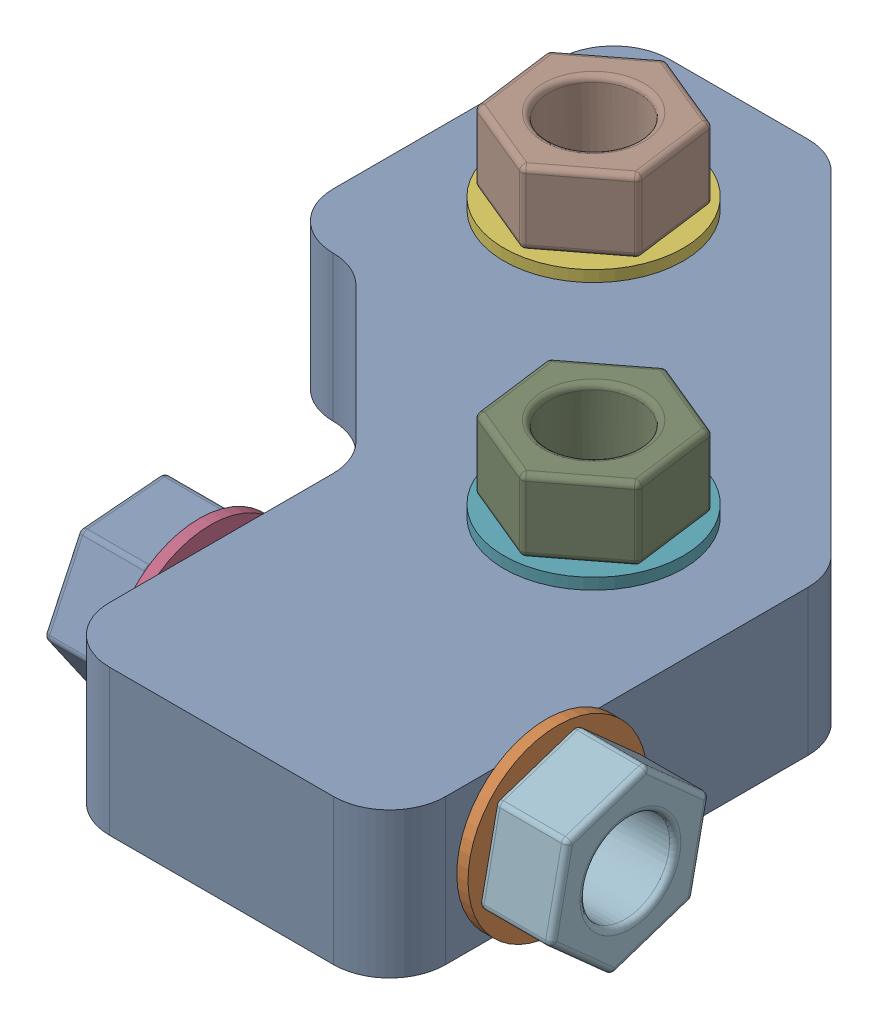
SolidWorks assembly Middle Corner with Washers and Nuts, configuration Default. Lengths in mm.
Overall size (59.5 28 72).
13 component instances, 3 part files, 12 mates.
Components (placement in the parent):
- Corner (Middle)-1: Corner (Middle) [Default] at origin size (52 13 72)
- M8 Washer 16mm-1: M8 Washer 16mm [Default] at (31 6.5 28) x (0 -0.996771 -0.080291) z (0 0.080291 -0.996771) size (16 1 16)
- M8 Washer 16mm-2: M8 Washer 16mm [Default] at (-8.7868 0 -15) x (0.471169 0 0.882043) z (0.882043 0 -0.471169) size (16 1 16)
- M8 Washer 16mm-3: M8 Washer 16mm [Default] at (0 6.5 28) x (0 -0.996771 -0.080291) z (0 0.080291 -0.996771) size (16 1 16)
- M8 Washer 16mm-4: M8 Washer 16mm [Default] at (15 0 8.7868) x (0.471169 0 0.882043) z (0.882043 0 -0.471169) size (16 1 16)
- M8 Washer 16mm-5: M8 Washer 16mm [Default] at (-8.7868 14 -15) x (0.471169 0 0.882043) z (0.882043 0 -0.471169) size (16 1 16)
- M8 Washer 16mm-6: M8 Washer 16mm [Default] at (15 14 8.7868) x (0.471169 0 0.882043) z (0.882043 0 -0.471169) size (16 1 16)
- M8 Nut-1: M8 Nut [Default] at (-8.7868 20.5 -15) x (0.130839 0 0.991404) z (0.991404 0 -0.130839) size (14.85 6.5 12.99)
- M8 Nut-2: M8 Nut [Default] at (15 20.5 8.7868) x (0.130839 0 0.991404) z (0.991404 0 -0.130839) size (14.85 6.5 12.99)
- M8 Nut-3: M8 Nut [Default] at (-8.7868 -7.5 -15) x (-0.876876 0 -0.480716) z (0.480716 0 -0.876876) size (14.85 6.5 12.99)
- M8 Nut-4: M8 Nut [Default] at (15 -7.5 8.7868) x (-0.876876 0 -0.480716) z (0.480716 0 -0.876876) size (14.85 6.5 12.99)
- M8 Nut-5: M8 Nut [Default] at (37.5 6.5 28) x (0 -0.313453 0.949604) z (0 -0.949604 -0.313453) size (14.85 6.5 12.99)
- M8 Nut-6: M8 Nut [Default] at (-7.5 6.5 28) x (0 -0.083835 0.99648) z (0 0.99648 0.083835) size (14.85 6.5 12.99)
Mates (geometry in assembly coordinates):
- Coincident14: coincident anti-aligned: circle of M8 Washer 16mm-6; circle of Corner (Middle)-1
- Coincident15: coincident anti-aligned: circle of M8 Washer 16mm-5; circle of Corner (Middle)-1
- Coincident16: coincident anti-aligned: circle of M8 Washer 16mm-4; circle of Corner (Middle)-1
- Coincident17: coincident anti-aligned: circle of M8 Washer 16mm-2; circle of Corner (Middle)-1
- Coincident18: coincident aligned: circle of M8 Washer 16mm-3; circle of Corner (Middle)-1
- Coincident19: coincident aligned: circle of M8 Washer 16mm-1; circle of Corner (Middle)-1
- Coincident22: coincident anti-aligned: circle of M8 Washer 16mm-1; circle of M8 Nut-5
- Coincident21: coincident aligned: circle of M8 Nut-3; circle of M8 Washer 16mm-2
- Coincident24: coincident aligned: circle of M8 Nut-6; circle of M8 Washer 16mm-3
- Coincident20: coincident aligned: circle of M8 Washer 16mm-4; circle of M8 Nut-4
- Coincident25: coincident anti-aligned: circle of M8 Washer 16mm-5; circle of M8 Nut-1
- Coincident26: coincident anti-aligned: circle of M8 Washer 16mm-6; circle of M8 Nut-2
